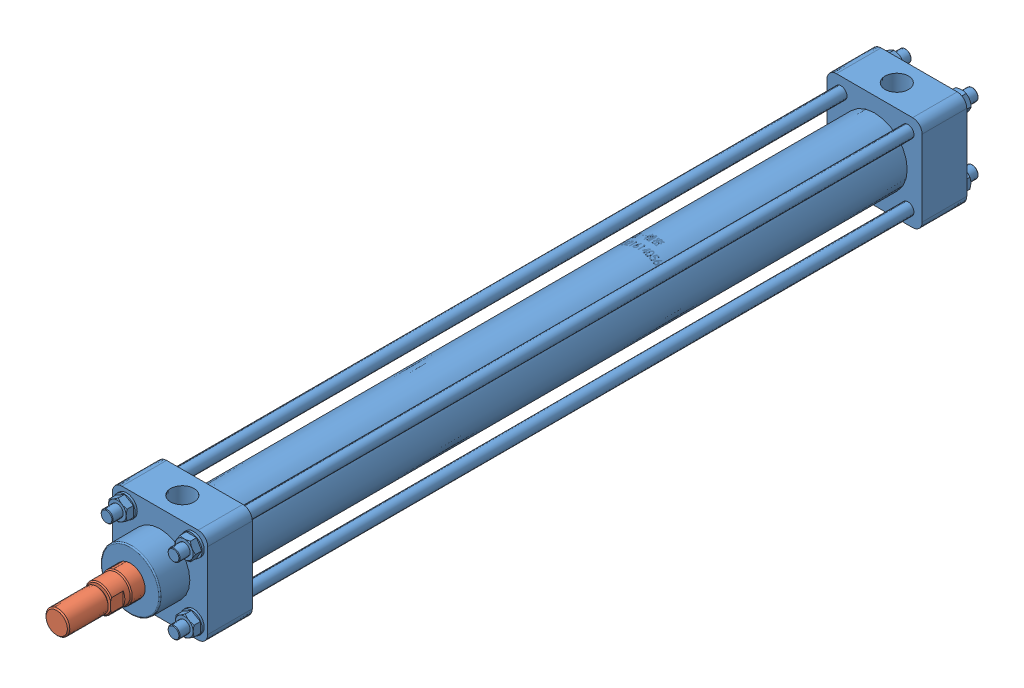
SolidWorks assembly MOB标准型中低压油缸[MOB-φ40×400], configuration MOB-φ40×400. Lengths in mm.
Overall size (64 64 592.86).
2 component instances, 2 part files, 3 mates.
Components (placement in the parent):
- MOB标准型中低压油缸[MOB-φ40×400]_缸体-1: MOB标准型中低压油缸[MOB-φ40×400]_缸体 [默认] at (25.7559 5.8137 0) size (64 64 543.44)
- MOB标准型中低压油缸[MOB-φ40×400]_杆-1: MOB标准型中低压油缸[MOB-φ40×400]_杆 [默认] at (25.7559 5.8137 4.4245) size (20 20 445)
Mates (geometry in assembly coordinates):
- 同心1: concentric anti-aligned: cylinder of 缸体-1 through (25.7559 5.8137 -450) axis (0 0 1) radius 10; cylinder of 杆-1 through (25.7559 5.8137 -395.5755) axis (0 0 -1) radius 10
- 重合1: coincident aligned: plane of 缸体-1 through (25.7559 5.8137 0) normal (1 0 0); plane of 杆-1 through (25.7559 5.8137 4.4245) normal (1 0 0)
- 路径配合1: path: point of MOB标准型中低压油缸[MOB-φ40×400]_杆-1; curve of MOB标准型中低压油缸[MOB-φ40×400]_缸体-1
